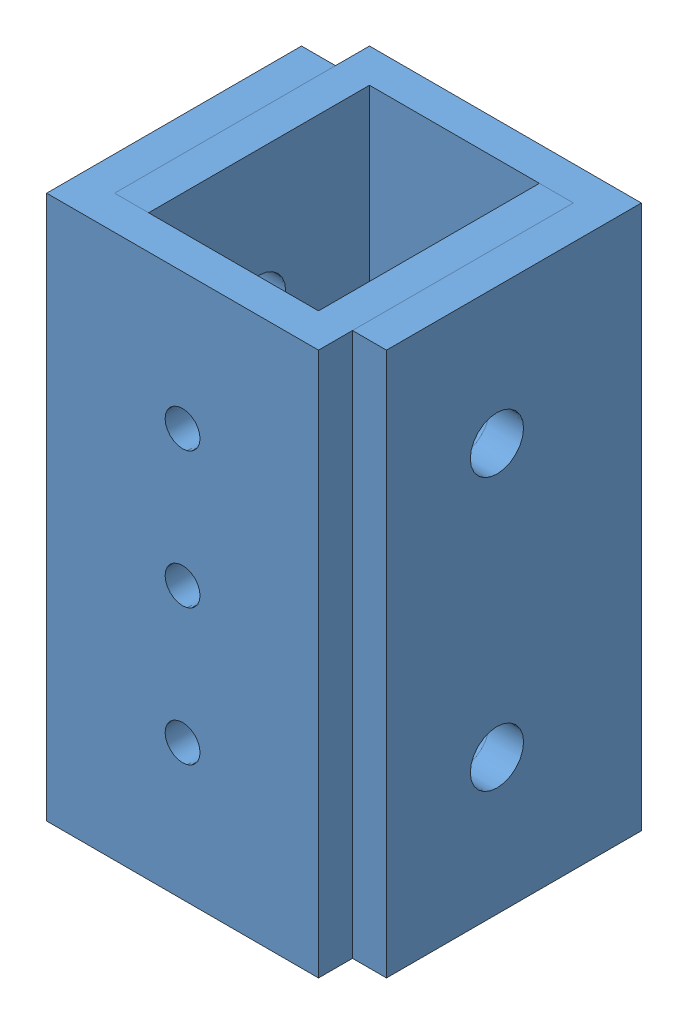
SolidWorks assembly 20-760 Mount Asm, configuration Default. Lengths in mm.
Overall size (28.57 50.8 26.99).
2 component instances, 1 part files, 3 mates.
Components (placement in the parent):
- 20-761 C-Channel-2: 20-761 C-Channel [Chain] at (-0.4319 3.2335 52.9895) size (25.4 50.8 23.81)
- 20-761 C-Channel-3: 20-761 C-Channel [Chassis] at (2.7431 54.0335 26.002) x (1 0 0) z (0 0 -1) size (25.4 50.8 23.81)
Mates (geometry in assembly coordinates):
- Coincident1: coincident aligned: plane of 20-761 C-Channel-2 through (-0.4319 3.2335 52.9895) normal (0 -1 0); plane of 20-761 C-Channel-3 through (2.7431 3.2335 26.002) normal (0 -1 0)
- Coincident2: coincident anti-aligned: plane of 20-761 C-Channel-2 through (24.9681 54.0335 29.177) normal (0 0 -1); plane of 20-761 C-Channel-3 through (24.9681 3.2335 29.177) normal (0 0 1)
- Coincident3: coincident anti-aligned: plane of 20-761 C-Channel-2 through (24.9681 54.0335 52.9895) normal (1 0 0); plane of 20-761 C-Channel-3 through (24.9681 3.2335 49.8145) normal (-1 0 0)
